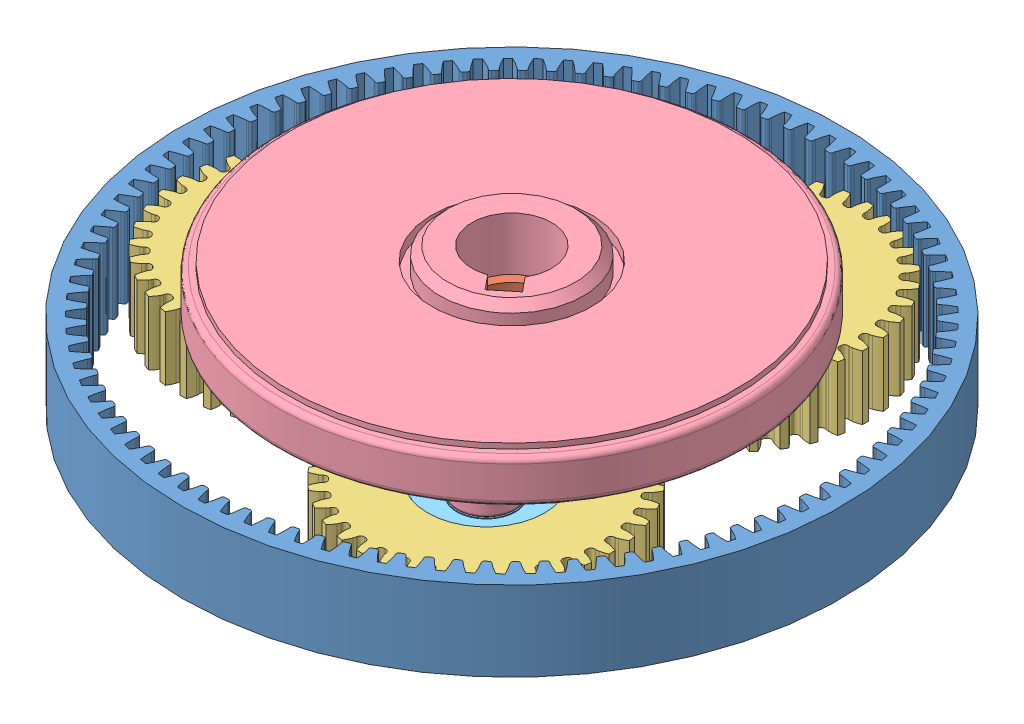
SolidWorks assembly Gearbox, configuration Default. Lengths in mm.
Overall size (124 30.5 124).
9 component instances, 5 part files, 16 mates.
Components (placement in the parent):
- Ring gear-1: Ring gear [Default] at (0.3036 -16.4275 5.905) size (124 15 124)
- Sun Gear-1: Sun Gear [Default] at (0.3036 -16.4275 5.905) x (0.79364 0 -0.608388) z (0.608388 0 0.79364) size (44 19 44)
- Planet Gear-1: Planet Gear [Default] at (-32.7686 -16.4275 11.2419) x (0.982222 0 -0.187723) z (0.187723 0 0.982222) size (47.5 12 47.5)
- Planet Gear-2: Planet Gear [Default] at (21.4615 -16.4275 31.8779) x (0.999992 0 0.003959) z (-0.003959 0 0.999992) size (47.5 12 47.5)
- Planet Gear-3: Planet Gear [Default] at (12.2177 -16.4275 -25.4047) x (0.019397 0 -0.999812) z (0.999812 0 0.019397) size (47.5 12 47.5)
- Planet Carrier-1: Planet Carrier [Default] at (0.3036 7.5725 5.905) x (0.77531 0 -0.631581) z (-0.631581 0 -0.77531) size (88 24.5 88)
- 608RS-1: 608RS [Default] at (21.4615 -6.9275 31.8779) x (0.04531 0 0.998973) z (0 -1 0) size (22 22 7)
- 608RS-2: 608RS [Default] at (12.2177 -6.9275 -25.4047) x (0.99979 0 -0.020484) z (0 -1 0) size (22 22 7)
- 608RS-3: 608RS [Default] at (-32.7686 -6.9275 11.2419) x (0.23389 0 0.972263) z (0 -1 0) size (22 22 7)
Mates (geometry in assembly coordinates):
- Concentric1: concentric: cylinder of assembly; cylinder of assembly; cylinder of Ring gear-1 through (0.3036 -16.4275 5.905) axis (0 1 0) radius 62; cylinder of Sun Gear-1 through (0.3036 -16.4275 5.905) axis (0 1 0) radius 7.75
- Coincident1: coincident: plane of assembly; plane of assembly; plane of Ring gear-1 through (0.3036 -16.4275 5.905) normal (0 -1 0); plane of Sun Gear-1 through (0.3036 -16.4275 5.905) normal (0 1 0)
- Coincident2: coincident: plane of assembly; plane of assembly; plane of Sun Gear-1 through (0.3036 -16.4275 5.905) normal (0 1 0); plane of Planet Gear-3 through (12.2177 -16.4275 -25.4047) normal (0 -1 0)
- Coincident3: coincident: plane of assembly; plane of assembly; plane of Sun Gear-1 through (0.3036 -16.4275 5.905) normal (0 1 0); plane of Planet Gear-1 through (-32.7686 -16.4275 11.2419) normal (0 -1 0)
- Coincident4: coincident: plane of assembly; plane of assembly; plane of Sun Gear-1 through (0.3036 -16.4275 5.905) normal (0 1 0); plane of Planet Gear-2 through (21.4615 -16.4275 31.8779) normal (0 -1 0)
- Concentric5: concentric: cylinder of assembly; cylinder of assembly; cylinder of Sun Gear-1 through (0.3036 -16.4275 5.905) axis (0 1 0) radius 7.75; cylinder of Planet Carrier-1 through (0.3036 65.5725 5.905) axis (0 -1 0) radius 7.5
- Concentric6: concentric: cylinder of Planet Gear-3 through (12.2177 -16.4275 -25.4047) axis (0 1 0) radius 11; cylinder of 608RS-2 through (12.2177 -13.9275 -25.4047) axis (0 1 0) radius 11
- Concentric7: concentric: cylinder of Planet Gear-1 through (-32.7686 -16.4275 11.2419) axis (0 1 0) radius 11; cylinder of 608RS-3 through (-32.7686 -13.9275 11.2419) axis (0 1 0) radius 11
- Concentric8: concentric: cylinder of Planet Gear-2 through (21.4615 -16.4275 31.8779) axis (0 1 0) radius 11; cylinder of 608RS-1 through (21.4615 -13.9275 31.8779) axis (0 1 0) radius 11
- Concentric9: concentric: cylinder of Planet Carrier-1 through (12.2177 -6.9275 -25.4047) axis (0 -1 0) radius 4; cylinder of 608RS-2 through (12.2177 -13.9275 -25.4047) axis (0 1 0) radius 4
- Concentric10: concentric: cylinder of Planet Carrier-1 through (-32.7686 -6.9275 11.2419) axis (0 -1 0) radius 4; cylinder of 608RS-3 through (-32.7686 -13.9275 11.2419) axis (0 1 0) radius 4
- Concentric11: concentric: cylinder of Planet Carrier-1 through (21.4615 -6.9275 31.8779) axis (0 -1 0) radius 4; cylinder of 608RS-1 through (21.4615 -13.9275 31.8779) axis (0 1 0) radius 4
- Coincident5: coincident: plane of Planet Carrier-1 through (-32.7686 -6.9275 11.2419) normal (0 -1 0); plane of 608RS-3 through (-32.7686 -6.9275 11.2419) normal (0 1 0)
- Coincident6: coincident: plane of Planet Carrier-1 through (21.4615 -6.9275 31.8779) normal (0 -1 0); plane of 608RS-1 through (21.4615 -6.9275 31.8779) normal (0 1 0)
- Coincident7: coincident: plane of Planet Carrier-1 through (12.2177 -6.9275 -25.4047) normal (0 -1 0); plane of 608RS-2 through (12.2177 -6.9275 -25.4047) normal (0 1 0)
- Distance1: distance = 2.5 mm: plane of 608RS-1 through (21.4615 -13.9275 31.8779) normal (0 -1 0); plane of Planet Gear-2 through (21.4615 -16.4275 31.8779) normal (0 -1 0)
